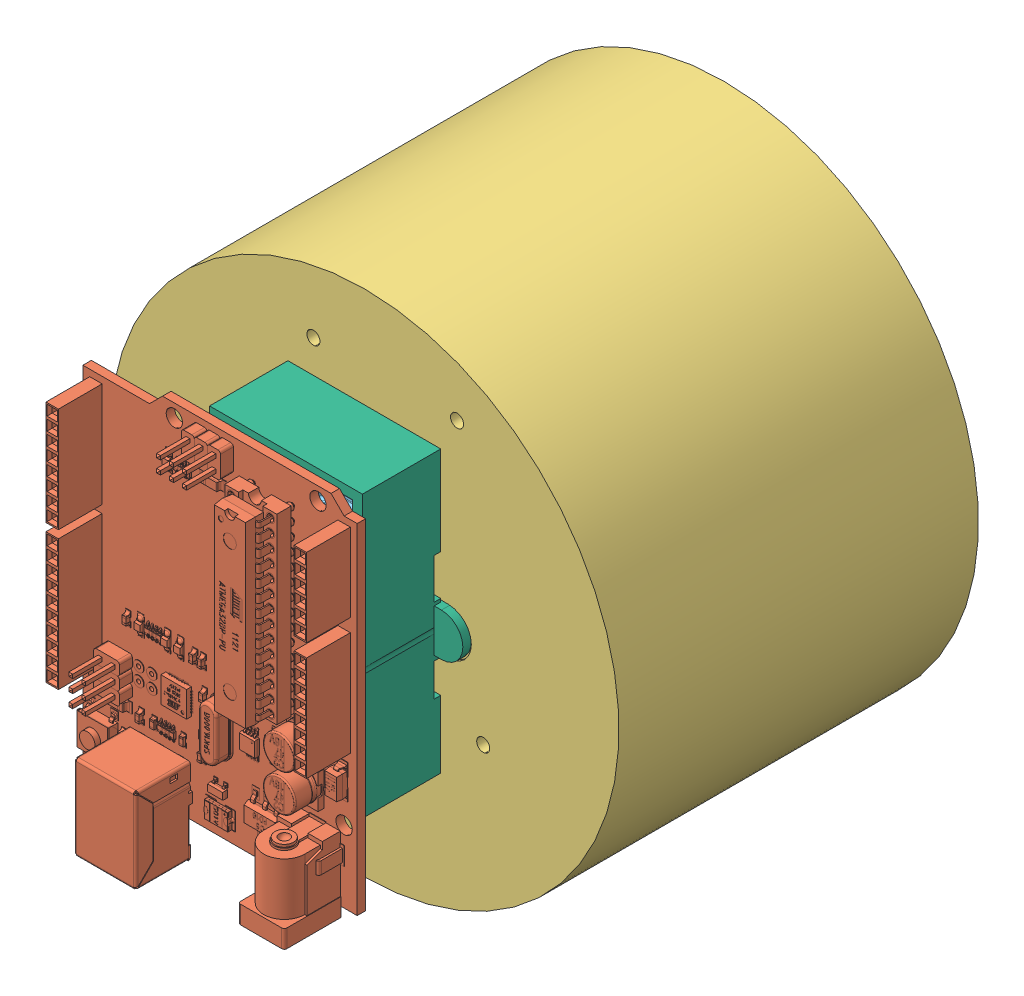
SolidWorks assembly Assem1, configuration Default. Lengths in mm.
Overall size (99.06 99.06 108.01).
6 component instances, 6 part files, 12 mates.
Components (placement in the parent):
- Motor-1: Motor [Default] at origin size (39.85 39.85 49.81)
- arduino uno-1: arduino uno [Default] at (25.654 -29.718 32.13) x (1 0 0) z (0 -1 0) size (53.34 15.25 74.93)
- Wheel-1: Wheel [Default] at origin size (99.06 99.06 69.91)
- Flywheel-1: Flywheel [Default] at (0 0 -45.6438) x (0.964282 -0.264877 0) z (0 0 1) size (63.5 63.5 5.08)
- 9V Battery-1: 9V Battery [Default] at (1.2046 -15.1491 5.6819) size (25.91 48.13 16.26)
- 9V Holder-1: 9V Holder [Default] at origin size (40.86 54.61 15.62)
Mates (geometry in assembly coordinates):
- Concentric1: concentric anti-aligned: cylinder of Motor-1 through (0 0 0) axis (0 0 -1) radius 1.9685; cylinder of Flywheel-1 through (0 0 -45.6438) axis (0 0 1) radius 3.1369
- Distance1: distance = 10.668 mm anti-aligned: plane of Motor-1 through (0 4.5022 -34.9758) normal (0 0 -1); plane of Flywheel-1 through (0.8309 3.0249 -45.6438) normal (0 0 1)
- Distance2: distance = 25.4 mm: plane of arduino uno-1 through (25.654 -29.718 30.48) normal (0 0 -1); plane of Wheel-1 through (0 0 5.08) normal (0 0 1)
- Coincident3: coincident: point of arduino uno-1; line of assembly
- Parallel2: parallel anti-aligned: plane of arduino uno-1 through (-27.686 -29.718 30.48) normal (-1 0 0); plane of assembly through (0 0 0) normal (1 0 0)
- Parallel4: parallel anti-aligned: plane of 9V Battery-1 through (-12.9609 22.5821 -4.2365) normal (-1 0 0); plane of 9V Holder-1 through (-12.954 0 20.32) normal (1 0 0)
- Parallel3: parallel anti-aligned: plane of 9V Battery-1 through (-12.9609 -22.6299 12.0195) normal (0 -1 0); plane of 9V Holder-1 through (0 -22.733 20.32) normal (0 1 0)
- Coincident6: coincident anti-aligned: plane of 9V Holder-1 through (0 0 11.43) normal (0 0 1); plane of 9V Battery-1 through (-12.9609 22.5821 11.43) normal (0 0 -1)
- Coincident7: coincident: unknown of ?
- Coincident8: coincident anti-aligned: plane of Wheel-1 through (0 0 5.08) normal (0 0 1); plane of 9V Holder-1 through (-10.4835 -10.4835 5.08) normal (0 0 -1)
- Concentric2: concentric anti-aligned: cylinder of 9V Holder-1 through (-16.265 0 6.35) axis (0 0 -1) radius 4.1656; cylinder of Wheel-1 through (-16.265 0 4.572) axis (0 0 1) radius 4.5466
- Concentric3: concentric anti-aligned: cylinder of Wheel-1 through (16.265 0 4.572) axis (0 0 1) radius 4.5466; cylinder of 9V Holder-1 through (16.265 0 6.35) axis (0 0 -1) radius 4.1656
